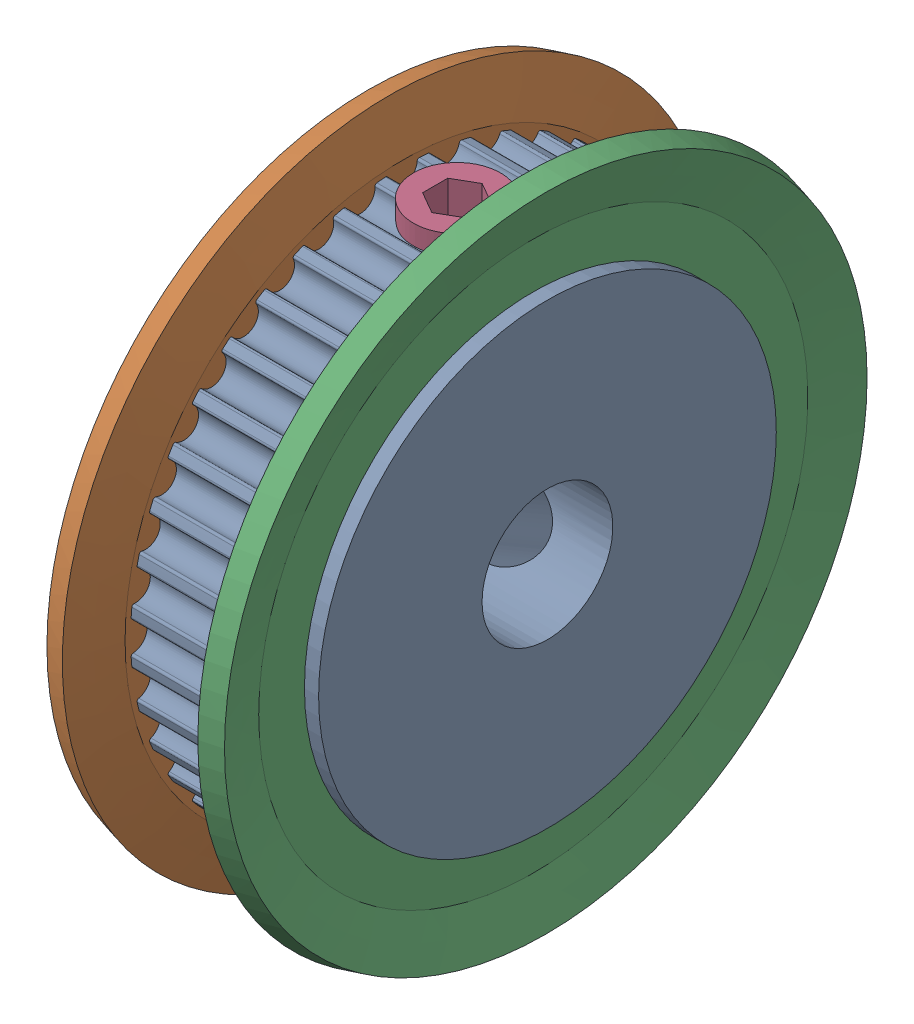
SolidWorks assembly Timing pulley_GPA40GT2040-A-P6_MISUMI, configuration Default. Lengths in mm.
Overall size (8.3 30 30).
5 component instances, 3 part files, 12 mates.
Components (placement in the parent):
- Timing Pulley_Timing pulley_GPA40GT2040-A-P6_MISUMI-1: Timing Pulley_Timing pulley_GPA40GT2040-A-P6_MISUMI [Default] at origin size (8.3 24.93 24.9)
- Flange_Timing pulley_GPA40GT2040-A-P6_MISUMI-1: Flange_Timing pulley_GPA40GT2040-A-P6_MISUMI [Default] at (0.65 0 0) size (1.57 30 30)
- Flange_Timing pulley_GPA40GT2040-A-P6_MISUMI-2: Flange_Timing pulley_GPA40GT2040-A-P6_MISUMI [Default] at (7.65 0 0) x (-1 0 0) z (0 0 -1) size (1.57 30 30)
- Set Screw-1_Timing pulley_GPA40GT2040-A-P6_MISUMI-1: Set Screw-1_Timing pulley_GPA40GT2040-A-P6_MISUMI [Default] at (4.15 9.475 0) size (4 3 4)
- Set Screw-1_Timing pulley_GPA40GT2040-A-P6_MISUMI-2: Set Screw-1_Timing pulley_GPA40GT2040-A-P6_MISUMI [Default] at (4.15 -4.7375 -8.2056) x (1 0 0) z (0 0.866025 -0.5) size (4 3 4)
Mates (geometry in assembly coordinates):
- Concentric1: concentric anti-aligned: cylinder of Timing Pulley_BaseModel20220421222855-1 through (0 0 0) axis (-1 0 0) radius 10.5; cylinder of Flange_BaseModel20220421222855-1 through (1.65 0 0) axis (1 0 0) radius 10.5
- Coincident1: coincident anti-aligned: plane of Timing Pulley_BaseModel20220421222855-1 through (1.65 10.5 0) normal (-1 0 0); plane of Flange_BaseModel20220421222855-1 through (1.65 10.5 0) normal (1 0 0)
- Coincident2: coincident aligned: plane of Timing Pulley_BaseModel20220421222855-1 through (0 0 0) normal (0 0 1); plane of Flange_BaseModel20220421222855-1 through (0.65 0 0) normal (0 0 1)
- Concentric2: concentric aligned: cylinder of Timing Pulley_BaseModel20220421222855-1 through (0 0 0) axis (-1 0 0) radius 10.5; cylinder of Flange_BaseModel20220421222855-2 through (6.65 0 0) axis (-1 0 0) radius 10.5
- Coincident3: coincident anti-aligned: plane of Timing Pulley_BaseModel20220421222855-1 through (6.65 10.5 0) normal (1 0 0); plane of Flange_BaseModel20220421222855-2 through (6.65 10.5 0) normal (-1 0 0)
- Coincident4: coincident anti-aligned: plane of Timing Pulley_BaseModel20220421222855-1 through (0 0 0) normal (0 0 1); plane of Flange_BaseModel20220421222855-2 through (7.65 0 0) normal (0 0 -1)
- Concentric3: concentric aligned: cylinder of Timing Pulley_BaseModel20220421222855-1 through (4.15 12.475 0) axis (0 1 0) radius 1.65; cylinder of Set Screw-1_BaseModel20220421222855-1 through (4.15 12.475 0) axis (0 1 0) radius 2
- Tangent1: tangent aligned: cylinder of Timing Pulley_BaseModel20220421222855-1 through (0 0 0) axis (-1 0 0) radius 12.475; plane of Set Screw-1_BaseModel20220421222855-1 through (4.15 12.475 0) normal (0 1 0)
- Concentric4: concentric aligned: cylinder of Timing Pulley_BaseModel20220421222855-1 through (4.15 -6.2375 -10.8037) axis (0 -0.5 -0.866025) radius 1.65; cylinder of Set Screw-1_BaseModel20220421222855-2 through (4.15 -6.2375 -10.8037) axis (0 -0.5 -0.866025) radius 2
- Tangent2: tangent aligned: cylinder of Timing Pulley_BaseModel20220421222855-1 through (0 0 0) axis (-1 0 0) radius 12.475; plane of Set Screw-1_BaseModel20220421222855-2 through (4.15 -6.2375 -10.8037) normal (0 -0.5 -0.866025)
- Parallel1: parallel aligned: plane of Timing Pulley_BaseModel20220421222855-1 through (0 0 0) normal (1 0 0); plane of Set Screw-1_BaseModel20220421222855-1 through (4.15 9.475 0) normal (1 0 0)
- Parallel2: parallel aligned: plane of Timing Pulley_BaseModel20220421222855-1 through (0 0 0) normal (1 0 0); plane of Set Screw-1_BaseModel20220421222855-2 through (4.15 -4.7375 -8.2056) normal (1 0 0)
